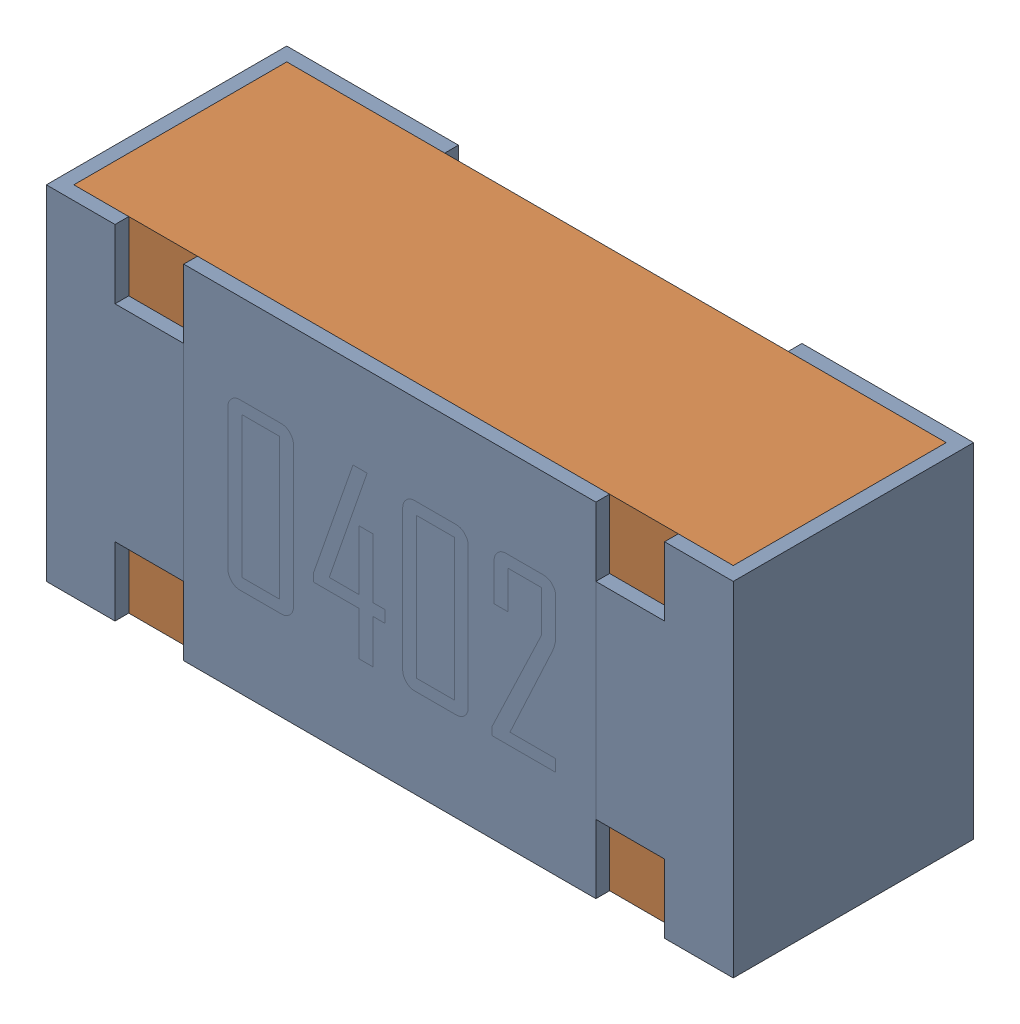
SolidWorks assembly R9, configuration Default. Lengths in mm.
Overall size (1 0.5 0.35).
3 component instances, 2 part files, 0 mates.
Components (placement in the parent):
- R9-subassembly-1-1: R9-subassembly-1 [Default] at (-9.0001 -11 0) x (1 0 0) z (0 -1 0) size (1 0.35 0.5)
  - 0402 resistor-1: 0402 resistor [Default] at origin size (1 0.35 0.5)
  - 0402 resistor-1-1: 0402 resistor-1 [Default] at origin size (0.96 0.31 0.5)
